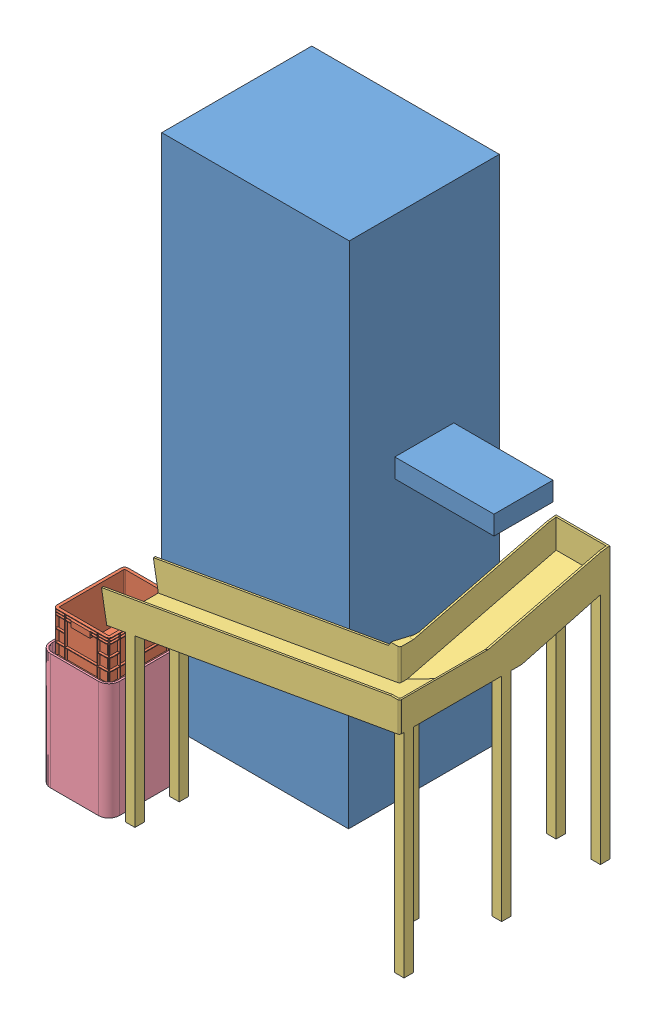
SolidWorks assembly assieme_disegno_scivolo_scarti, configuration Default. Lengths in mm.
Overall size (2027 2934.69 1423.1).
4 component instances, 4 part files, 11 mates.
Components (placement in the parent):
- Macchina_Test-1: Macchina_Test [Default] at (-535.3477 -210.1986 245.0499) size (1727 2934.69 870.1)
- box-1: box [Default] at (-783.2088 -1202.6318 2823.0499) x (0 0 1) z (-1 0 0) size (381 240 293)
- Parte1^assieme_disegno_scivolo_scarti-1: Parte1^assieme_disegno_scivolo_scarti [Default] at (-535.3477 -281.554 245.0499) x (-1 0 0) z (0 -1 0) size (1571.21 1106.16 1428.64) (virtual)
- Parte2^assieme_disegno_scivolo_scarti-1: Parte2^assieme_disegno_scivolo_scarti [Default] at (-783.2088 -1197.6318 2823.0499) x (0 0 -1) z (0 -1 0) size (445 363 612.57) (virtual)
Mates (geometry in assembly coordinates):
- Perpendicolare1: perpendicular: plane of Macchina_Test-1 through (-771.2088 -1070.8886 1855.0499) normal (0 0 -1); plane of box-1 through (-771.2088 -1115.6318 2843.0499) normal (-1 0 0)
- Coincidente7: coincident aligned: plane of Macchina_Test-1 through (-771.2088 -1070.8886 1855.0499) normal (-1 0 0); plane of box-1 through (-771.2088 -1115.6318 2843.0499) normal (-1 0 0)
- SulPosto1: in place: plane of Macchina_Test-1 through (734.7912 -281.554 2395.3876) normal (0 -1 0); plane of ? through (0 -281.554 0) normal (0 -1 0); moOrthogonalPlaneRef_w of Macchina_Test-1 through (734.7912 -281.554 2395.3876) normal (0 -1 0); plane of ? through (0 -281.554 0) normal (0 0 -1); plane of Macchina_Test-1 through (734.7912 -281.554 2395.3876) normal (0 -1 0); plane of ? through (0 -281.554 0) normal (-1 0 0); plane of Macchina_Test-1 through (734.7912 -281.554 2395.3876) normal (0 -1 0); unknown of Parte1^assieme_disegno_scivolo_scarti-1
- Coincidente8: coincident aligned: plane of Macchina_Test-1; plane of Parte1^assieme_disegno_scivolo_scarti-1
- Coincidente9: coincident aligned: moOrthogonalPlaneRef_w of Macchina_Test-1 through (-535.3477 -281.554 245.0499) normal (0 0 -1); plane of Parte1^assieme_disegno_scivolo_scarti-1 through (-535.3477 -281.554 245.0499) normal (0 0 -1)
- Coincidente10: coincident anti-aligned: moOrthogonalPlaneRef_w of Macchina_Test-1 through (-535.3477 -281.554 245.0499) normal (1 0 0); plane of Parte1^assieme_disegno_scivolo_scarti-1 through (-535.3477 -281.554 245.0499) normal (-1 0 0)
- Distanza6: distance = 200 mm anti-aligned: plane of box-1 through (-510.2088 -1115.6318 2835.0499) normal (0 0 -1); plane of Macchina_Test-1 through (-771.2088 -1070.8886 2635.0499) normal (0 0 1)
- SulPosto2: in place: plane of box-1 through (-783.2088 -1197.6318 2823.0499) normal (0 -1 0); plane of ? through (0 -1197.6318 0) normal (0 -1 0); plane of box-1 through (-783.2088 -1197.6318 2823.0499) normal (0 -1 0); plane of ? through (0 -1197.6318 0) normal (0 0 -1); plane of box-1 through (-783.2088 -1197.6318 2823.0499) normal (0 -1 0); plane of ? through (0 -1197.6318 0) normal (-1 0 0); plane of box-1 through (-783.2088 -1197.6318 2823.0499) normal (0 -1 0); unknown of Parte2^assieme_disegno_scivolo_scarti-1
- Coincidente8: coincident aligned: plane of box-1; plane of Parte2^assieme_disegno_scivolo_scarti-1
- Coincidente9: coincident aligned: moOrthogonalPlaneRef_w of box-1 through (-783.2088 -1197.6318 2823.0499) normal (1 0 0); plane of Parte2^assieme_disegno_scivolo_scarti-1 through (-783.2088 -1197.6318 2823.0499) normal (1 0 0)
- Coincidente10: coincident anti-aligned: moOrthogonalPlaneRef_w of box-1 through (-783.2088 -1197.6318 2823.0499) normal (0 0 1); plane of Parte2^assieme_disegno_scivolo_scarti-1 through (-783.2088 -1197.6318 2823.0499) normal (0 0 -1)
